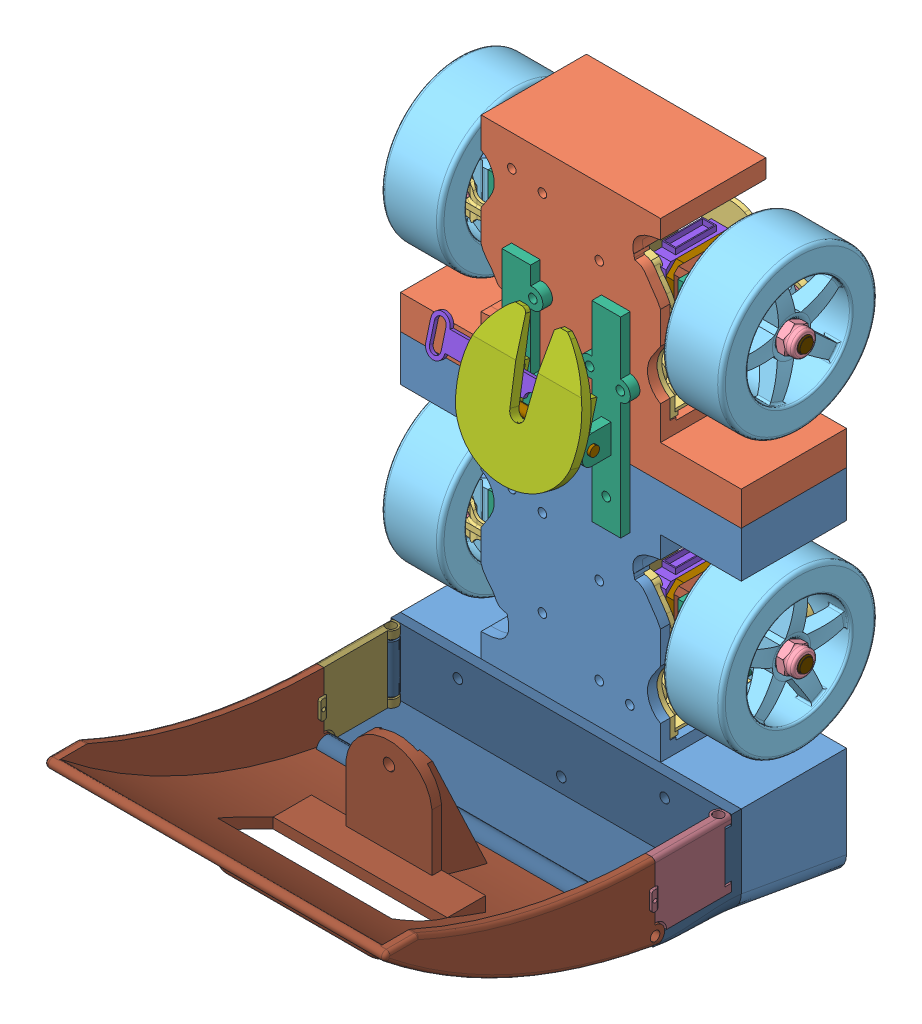
SolidWorks assembly Chassis assembly 2, configuration Default. Lengths in mm.
Overall size (185.37 311.7 273.69).
160 component instances, 31 part files, 34 mates.
Components (placement in the parent):
- Dolly chassis half 1-1: Dolly chassis half 1 [Default] at (2.6348 264.5467 189.9496) size (178 185.23 55)
- Dolly chassis half 2-1: Dolly chassis half 2 [Default] at (2.6348 264.5467 189.9496) size (178 119.07 55)
- Module Assembly-1: Module Assembly [Default] at (-63.8652 93.3967 162.4496) x (0 -1 0) z (-1 0 0) size (68.25 51.28 97.81)
  - Housing-1: Housing [Default] at origin size (64.25 48.5 67.91)
  - Bearing 12x8-1: Bearing 12x8 [Default] at (0 -18.25 0.75) x (-0.914388 0 0.40484) z (-0.40484 0 -0.914388) size (12 3.5 12)
  - Spindle-1: Spindle [Default] at (0 2 0.75) size (49.04 45 20.5)
  - Spindle base-1: Spindle base [Default] at (0 2 -15.25) x (-1 0 0) z (0 -1 0) size (37.62 3.5 44.8)
  - Encoder-1: Encoder [Défaut] at (0 2 -12.48) x (0 1 0) z (0 0 1) size (28.68 37.25 10.4)
  - Wheel-1: Wheel [Default] at (0 2 -8.55) x (0.929787 0.368098 0) z (0.368098 -0.929787 0) size (81.5 31 81.5) (hidden)
  - Stepper Nema14-1: Stepper Nema14 [Predeterminado] at (4.764 -15.5 -30.1157) x (-1 0 0) z (0 1 0) size (37.8 40 35)
    - nema14_base-1: nema14_base [Predeterminado] at (-12.736 -8.6343 35) size (37.8 9 35)
    - nema14_centro-1: nema14_centro [Predeterminado] at (-12.736 0.3657 35) size (35 4 35)
    - nema14_eje-1: nema14_eje [Predeterminado] at (4.764 -6.6343 17.5) x (0 1 0) z (-0.939004 0 0.343907) size (38 5 5)
    - nema14_techo-1: nema14_techo [Predeterminado] at (-12.736 4.3657 35) size (35 9 35)
  - Servo motor-1: Servo motor [Default] at (-25.7048 26.288 -66.0832) x (0 0 1) z (1 0 0) size (11.5 29.2 32.5) (flexible)
    - TowerPro-SG90-Body-1: TowerPro-SG90-Body [Default] at (13.6721 7.288 30.7048) size (11.5 26 32.5)
    - ServoFinalGear-1: ServoFinalGear [Default] at (13.6721 33.288 25.7048) x (0.607544 0 -0.794286) z (0.794286 0 0.607544) size (4.64 3.2 4.64)
  - Control arm-1: Control arm [Default] at (0 -7.5 -52.4111) x (0.891007 0 0.45399) z (0.45399 0 -0.891007) size (37.9 4.5 7.8)
  - Ball joint assy-1: Ball joint assy [Default] at (-26.7302 -5 -12.8697) x (-0.874356 0 0.485286) z (0.485286 0 0.874356) size (15.43 16.21 22.24) (flexible)
    - Ball-1: Ball [Default] at origin size (5.5 15.11 5.5)
    - Joint-1: Joint [Default] at (-3.8823 13.66 -6.9948) x (0.874356 0 -0.485286) z (0 -1 0) size (5.1 22.6 5.1)
  - Ball joint assy-2: Ball joint assy [Default] at (-26.7302 -5 -66.0308) x (-0.846813 0 0.531891) z (0.531891 0 0.846813) size (16.34 16.21 21.85) (flexible)
    - Ball-1: Ball [Default] at origin size (5.5 15.11 5.5)
    - Joint-1: Joint [Default] at (4.2551 13.66 6.7745) x (-0.846813 0 0.531891) z (0 -1 0) size (5.1 22.6 5.1)
  - Steering rod-1: Steering rod [Default] at (-26.7302 -18.66 -18.4608) x (-0.014502 0.999895 0) z (-0.999895 -0.014502 0) size (3 28.27 3)
  - Wheel adapter-1: Wheel adapter [Default] at (0 2 -13.8175) x (0.291296 -0.956633 0) z (-0.956633 -0.291296 0) size (8.34 40 8.37)
  - Wheel spacer-1: Wheel spacer [Default] at (0 2 12.25) x (0.368098 -0.929787 0) z (0.929787 0.368098 0) size (13.86 8 12)
  - M3x5 din 7984-1: M3x5 din 7984 [Default] at (15.31 20.9 -16.25) x (0.933505 0.358563 0) z (0 0 -1) size (5.5 5.5 7)
  - Housing lid-1: Housing lid [Default] at (0 4 0) x (-1 0 0) z (0 0 1) size (68.25 9.28 69.91)
  - Bearing 12x8-3: Bearing 12x8 [Default] at (0 22.25 0.75) x (-0.914388 0 0.40484) z (0.40484 0 0.914388) size (12 3.5 12)
  - M8 nut-1: M8 nut [Default] at (0 2 16.6825) x (-0.817347 -0.576146 0) z (0 0 1) size (13 16.06 8.5)
  - M3x5 din 7984-2: M3x5 din 7984 [Default] at (15.31 -16.9 -16.25) x (-0.933505 0.358563 0) z (0 0 -1) size (5.5 5.5 7)
  - M3x5 din 7984-3: M3x5 din 7984 [Default] at (-15.31 20.9 -16.25) x (0.933505 -0.358563 0) z (0 0 -1) size (5.5 5.5 7)
  - M3x5 din 7984-4: M3x5 din 7984 [Default] at (-15.31 -16.9 -16.25) x (-0.933505 -0.358563 0) z (0 0 -1) size (5.5 5.5 7)
  - M3x5 din 7984-5: M3x5 din 7984 [Default] at (-13 15 -17.75) x (0.999849 0.017374 0) z (0 0 1) size (5.5 5.5 7)
  - M3x5 din 7984-6: M3x5 din 7984 [Default] at (-13 -11 -17.75) x (-0.999849 0.017374 0) z (0 0 1) size (5.5 5.5 7)
  - M3x5 din 7984-7: M3x5 din 7984 [Default] at (13 15 -17.75) x (0.999849 -0.017374 0) z (0 0 1) size (5.5 5.5 7)
  - M3x5 din 7984-8: M3x5 din 7984 [Default] at (13 -11 -17.75) x (-0.999849 -0.017374 0) z (0 0 1) size (5.5 5.5 7)
- Module Assembly-2: Module Assembly [Default] at (69.1348 93.3967 162.4496) x (0 1 0) z (1 0 0) size (68.25 51.28 97.81)
  - Housing-1: Housing [Default] at origin size (64.25 48.5 67.91)
  - Bearing 12x8-1: Bearing 12x8 [Default] at (0 -18.25 0.75) x (-0.914388 0 0.40484) z (-0.40484 0 -0.914388) size (12 3.5 12)
  - Spindle-1: Spindle [Default] at (0 2 0.75) size (49.04 45 20.5)
  - Spindle base-1: Spindle base [Default] at (0 2 -15.25) x (-1 0 0) z (0 -1 0) size (37.62 3.5 44.8)
  - Encoder-1: Encoder [Défaut] at (0 2 -12.48) x (0 1 0) z (0 0 1) size (28.68 37.25 10.4)
  - Wheel-1: Wheel [Default] at (0 2 -8.55) x (0.929787 0.368098 0) z (0.368098 -0.929787 0) size (81.5 31 81.5) (hidden)
  - Stepper Nema14-1: Stepper Nema14 [Predeterminado] at (4.764 -15.5 -30.1157) x (-1 0 0) z (0 1 0) size (37.8 40 35)
    - nema14_base-1: nema14_base [Predeterminado] at (-12.736 -8.6343 35) size (37.8 9 35)
    - nema14_centro-1: nema14_centro [Predeterminado] at (-12.736 0.3657 35) size (35 4 35)
    - nema14_eje-1: nema14_eje [Predeterminado] at (4.764 -6.6343 17.5) x (0 1 0) z (-0.939004 0 0.343907) size (38 5 5)
    - nema14_techo-1: nema14_techo [Predeterminado] at (-12.736 4.3657 35) size (35 9 35)
  - Servo motor-1: Servo motor [Default] at (-25.7048 26.288 -66.0832) x (0 0 1) z (1 0 0) size (11.5 29.2 32.5) (flexible)
    - TowerPro-SG90-Body-1: TowerPro-SG90-Body [Default] at (13.6721 7.288 30.7048) size (11.5 26 32.5)
    - ServoFinalGear-1: ServoFinalGear [Default] at (13.6721 33.288 25.7048) x (0.607544 0 -0.794286) z (0.794286 0 0.607544) size (4.64 3.2 4.64)
  - Control arm-1: Control arm [Default] at (0 -7.5 -52.4111) x (0.891007 0 0.45399) z (0.45399 0 -0.891007) size (37.9 4.5 7.8)
  - Ball joint assy-1: Ball joint assy [Default] at (-26.7302 -5 -12.8697) x (-0.874356 0 0.485286) z (0.485286 0 0.874356) size (15.43 16.21 22.24) (flexible)
    - Ball-1: Ball [Default] at origin size (5.5 15.11 5.5)
    - Joint-1: Joint [Default] at (-3.8823 13.66 -6.9948) x (0.874356 0 -0.485286) z (0 -1 0) size (5.1 22.6 5.1)
  - Ball joint assy-2: Ball joint assy [Default] at (-26.7302 -5 -66.0308) x (-0.846813 0 0.531891) z (0.531891 0 0.846813) size (16.34 16.21 21.85) (flexible)
    - Ball-1: Ball [Default] at origin size (5.5 15.11 5.5)
    - Joint-1: Joint [Default] at (4.2551 13.66 6.7745) x (-0.846813 0 0.531891) z (0 -1 0) size (5.1 22.6 5.1)
  - Steering rod-1: Steering rod [Default] at (-26.7302 -18.66 -18.4608) x (-0.014502 0.999895 0) z (-0.999895 -0.014502 0) size (3 28.27 3)
  - Wheel adapter-1: Wheel adapter [Default] at (0 2 -13.8175) x (0.291296 -0.956633 0) z (-0.956633 -0.291296 0) size (8.34 40 8.37)
  - Wheel spacer-1: Wheel spacer [Default] at (0 2 12.25) x (0.368098 -0.929787 0) z (0.929787 0.368098 0) size (13.86 8 12)
  - M3x5 din 7984-1: M3x5 din 7984 [Default] at (15.31 20.9 -16.25) x (0.933505 0.358563 0) z (0 0 -1) size (5.5 5.5 7)
  - Housing lid-1: Housing lid [Default] at (0 4 0) x (-1 0 0) z (0 0 1) size (68.25 9.28 69.91)
  - Bearing 12x8-3: Bearing 12x8 [Default] at (0 22.25 0.75) x (-0.914388 0 0.40484) z (0.40484 0 0.914388) size (12 3.5 12)
  - M8 nut-1: M8 nut [Default] at (0 2 16.6825) x (-0.817347 -0.576146 0) z (0 0 1) size (13 16.06 8.5)
  - M3x5 din 7984-2: M3x5 din 7984 [Default] at (15.31 -16.9 -16.25) x (-0.933505 0.358563 0) z (0 0 -1) size (5.5 5.5 7)
  - M3x5 din 7984-3: M3x5 din 7984 [Default] at (-15.31 20.9 -16.25) x (0.933505 -0.358563 0) z (0 0 -1) size (5.5 5.5 7)
  - M3x5 din 7984-4: M3x5 din 7984 [Default] at (-15.31 -16.9 -16.25) x (-0.933505 -0.358563 0) z (0 0 -1) size (5.5 5.5 7)
  - M3x5 din 7984-5: M3x5 din 7984 [Default] at (-13 15 -17.75) x (0.999849 0.017374 0) z (0 0 1) size (5.5 5.5 7)
  - M3x5 din 7984-6: M3x5 din 7984 [Default] at (-13 -11 -17.75) x (-0.999849 0.017374 0) z (0 0 1) size (5.5 5.5 7)
  - M3x5 din 7984-7: M3x5 din 7984 [Default] at (13 15 -17.75) x (0.999849 -0.017374 0) z (0 0 1) size (5.5 5.5 7)
  - M3x5 din 7984-8: M3x5 din 7984 [Default] at (13 -11 -17.75) x (-0.999849 -0.017374 0) z (0 0 1) size (5.5 5.5 7)
- Module Assembly-3: Module Assembly [Default] at (69.1348 238.0467 162.4496) x (0 1 0) z (1 0 0) size (68.25 51.28 97.81)
  - Housing-1: Housing [Default] at origin size (64.25 48.5 67.91)
  - Bearing 12x8-1: Bearing 12x8 [Default] at (0 -18.25 0.75) x (-0.914388 0 0.40484) z (-0.40484 0 -0.914388) size (12 3.5 12)
  - Spindle-1: Spindle [Default] at (0 2 0.75) size (49.04 45 20.5)
  - Spindle base-1: Spindle base [Default] at (0 2 -15.25) x (-1 0 0) z (0 -1 0) size (37.62 3.5 44.8)
  - Encoder-1: Encoder [Défaut] at (0 2 -12.48) x (0 1 0) z (0 0 1) size (28.68 37.25 10.4)
  - Wheel-1: Wheel [Default] at (0 2 -8.55) x (0.929787 0.368098 0) z (0.368098 -0.929787 0) size (81.5 31 81.5) (hidden)
  - Stepper Nema14-1: Stepper Nema14 [Predeterminado] at (4.764 -15.5 -30.1157) x (-1 0 0) z (0 1 0) size (37.8 40 35)
    - nema14_base-1: nema14_base [Predeterminado] at (-12.736 -8.6343 35) size (37.8 9 35)
    - nema14_centro-1: nema14_centro [Predeterminado] at (-12.736 0.3657 35) size (35 4 35)
    - nema14_eje-1: nema14_eje [Predeterminado] at (4.764 -6.6343 17.5) x (0 1 0) z (-0.939004 0 0.343907) size (38 5 5)
    - nema14_techo-1: nema14_techo [Predeterminado] at (-12.736 4.3657 35) size (35 9 35)
  - Servo motor-1: Servo motor [Default] at (-25.7048 26.288 -66.0832) x (0 0 1) z (1 0 0) size (11.5 29.2 32.5) (flexible)
    - TowerPro-SG90-Body-1: TowerPro-SG90-Body [Default] at (13.6721 7.288 30.7048) size (11.5 26 32.5)
    - ServoFinalGear-1: ServoFinalGear [Default] at (13.6721 33.288 25.7048) x (0.607544 0 -0.794286) z (0.794286 0 0.607544) size (4.64 3.2 4.64)
  - Control arm-1: Control arm [Default] at (0 -7.5 -52.4111) x (0.891007 0 0.45399) z (0.45399 0 -0.891007) size (37.9 4.5 7.8)
  - Ball joint assy-1: Ball joint assy [Default] at (-26.7302 -5 -12.8697) x (-0.874356 0 0.485286) z (0.485286 0 0.874356) size (15.43 16.21 22.24) (flexible)
    - Ball-1: Ball [Default] at origin size (5.5 15.11 5.5)
    - Joint-1: Joint [Default] at (-3.8823 13.66 -6.9948) x (0.874356 0 -0.485286) z (0 -1 0) size (5.1 22.6 5.1)
  - Ball joint assy-2: Ball joint assy [Default] at (-26.7302 -5 -66.0308) x (-0.846813 0 0.531891) z (0.531891 0 0.846813) size (16.34 16.21 21.85) (flexible)
    - Ball-1: Ball [Default] at origin size (5.5 15.11 5.5)
    - Joint-1: Joint [Default] at (4.2551 13.66 6.7745) x (-0.846813 0 0.531891) z (0 -1 0) size (5.1 22.6 5.1)
  - Steering rod-1: Steering rod [Default] at (-26.7302 -18.66 -18.4608) x (-0.014502 0.999895 0) z (-0.999895 -0.014502 0) size (3 28.27 3)
  - Wheel adapter-1: Wheel adapter [Default] at (0 2 -13.8175) x (0.291296 -0.956633 0) z (-0.956633 -0.291296 0) size (8.34 40 8.37)
  - Wheel spacer-1: Wheel spacer [Default] at (0 2 12.25) x (0.368098 -0.929787 0) z (0.929787 0.368098 0) size (13.86 8 12)
  - M3x5 din 7984-1: M3x5 din 7984 [Default] at (15.31 20.9 -16.25) x (0.933505 0.358563 0) z (0 0 -1) size (5.5 5.5 7)
  - Housing lid-1: Housing lid [Default] at (0 4 0) x (-1 0 0) z (0 0 1) size (68.25 9.28 69.91)
  - Bearing 12x8-3: Bearing 12x8 [Default] at (0 22.25 0.75) x (-0.914388 0 0.40484) z (0.40484 0 0.914388) size (12 3.5 12)
  - M8 nut-1: M8 nut [Default] at (0 2 16.6825) x (-0.817347 -0.576146 0) z (0 0 1) size (13 16.06 8.5)
  - M3x5 din 7984-2: M3x5 din 7984 [Default] at (15.31 -16.9 -16.25) x (-0.933505 0.358563 0) z (0 0 -1) size (5.5 5.5 7)
  - M3x5 din 7984-3: M3x5 din 7984 [Default] at (-15.31 20.9 -16.25) x (0.933505 -0.358563 0) z (0 0 -1) size (5.5 5.5 7)
  - M3x5 din 7984-4: M3x5 din 7984 [Default] at (-15.31 -16.9 -16.25) x (-0.933505 -0.358563 0) z (0 0 -1) size (5.5 5.5 7)
  - M3x5 din 7984-5: M3x5 din 7984 [Default] at (-13 15 -17.75) x (0.999849 0.017374 0) z (0 0 1) size (5.5 5.5 7)
  - M3x5 din 7984-6: M3x5 din 7984 [Default] at (-13 -11 -17.75) x (-0.999849 0.017374 0) z (0 0 1) size (5.5 5.5 7)
  - M3x5 din 7984-7: M3x5 din 7984 [Default] at (13 15 -17.75) x (0.999849 -0.017374 0) z (0 0 1) size (5.5 5.5 7)
  - M3x5 din 7984-8: M3x5 din 7984 [Default] at (13 -11 -17.75) x (-0.999849 -0.017374 0) z (0 0 1) size (5.5 5.5 7)
- Module Assembly-4: Module Assembly [Default] at (-63.8652 238.0467 162.4496) x (0 -1 0) z (-1 0 0) size (68.25 51.28 97.81)
  - Housing-1: Housing [Default] at origin size (64.25 48.5 67.91)
  - Bearing 12x8-1: Bearing 12x8 [Default] at (0 -18.25 0.75) x (-0.914388 0 0.40484) z (-0.40484 0 -0.914388) size (12 3.5 12)
  - Spindle-1: Spindle [Default] at (0 2 0.75) size (49.04 45 20.5)
  - Spindle base-1: Spindle base [Default] at (0 2 -15.25) x (-1 0 0) z (0 -1 0) size (37.62 3.5 44.8)
  - Encoder-1: Encoder [Défaut] at (0 2 -12.48) x (0 1 0) z (0 0 1) size (28.68 37.25 10.4)
  - Wheel-1: Wheel [Default] at (0 2 -8.55) x (0.929787 0.368098 0) z (0.368098 -0.929787 0) size (81.5 31 81.5) (hidden)
  - Stepper Nema14-1: Stepper Nema14 [Predeterminado] at (4.764 -15.5 -30.1157) x (-1 0 0) z (0 1 0) size (37.8 40 35)
    - nema14_base-1: nema14_base [Predeterminado] at (-12.736 -8.6343 35) size (37.8 9 35)
    - nema14_centro-1: nema14_centro [Predeterminado] at (-12.736 0.3657 35) size (35 4 35)
    - nema14_eje-1: nema14_eje [Predeterminado] at (4.764 -6.6343 17.5) x (0 1 0) z (-0.939004 0 0.343907) size (38 5 5)
    - nema14_techo-1: nema14_techo [Predeterminado] at (-12.736 4.3657 35) size (35 9 35)
  - Servo motor-1: Servo motor [Default] at (-25.7048 26.288 -66.0832) x (0 0 1) z (1 0 0) size (11.5 29.2 32.5) (flexible)
    - TowerPro-SG90-Body-1: TowerPro-SG90-Body [Default] at (13.6721 7.288 30.7048) size (11.5 26 32.5)
    - ServoFinalGear-1: ServoFinalGear [Default] at (13.6721 33.288 25.7048) x (0.607544 0 -0.794286) z (0.794286 0 0.607544) size (4.64 3.2 4.64)
  - Control arm-1: Control arm [Default] at (0 -7.5 -52.4111) x (0.891007 0 0.45399) z (0.45399 0 -0.891007) size (37.9 4.5 7.8)
  - Ball joint assy-1: Ball joint assy [Default] at (-26.7302 -5 -12.8697) x (-0.874356 0 0.485286) z (0.485286 0 0.874356) size (15.43 16.21 22.24) (flexible)
    - Ball-1: Ball [Default] at origin size (5.5 15.11 5.5)
    - Joint-1: Joint [Default] at (-3.8823 13.66 -6.9948) x (0.874356 0 -0.485286) z (0 -1 0) size (5.1 22.6 5.1)
  - Ball joint assy-2: Ball joint assy [Default] at (-26.7302 -5 -66.0308) x (-0.846813 0 0.531891) z (0.531891 0 0.846813) size (16.34 16.21 21.85) (flexible)
    - Ball-1: Ball [Default] at origin size (5.5 15.11 5.5)
    - Joint-1: Joint [Default] at (4.2551 13.66 6.7745) x (-0.846813 0 0.531891) z (0 -1 0) size (5.1 22.6 5.1)
  - Steering rod-1: Steering rod [Default] at (-26.7302 -18.66 -18.4608) x (-0.014502 0.999895 0) z (-0.999895 -0.014502 0) size (3 28.27 3)
  - Wheel adapter-1: Wheel adapter [Default] at (0 2 -13.8175) x (0.291296 -0.956633 0) z (-0.956633 -0.291296 0) size (8.34 40 8.37)
  - Wheel spacer-1: Wheel spacer [Default] at (0 2 12.25) x (0.368098 -0.929787 0) z (0.929787 0.368098 0) size (13.86 8 12)
  - M3x5 din 7984-1: M3x5 din 7984 [Default] at (15.31 20.9 -16.25) x (0.933505 0.358563 0) z (0 0 -1) size (5.5 5.5 7)
  - Housing lid-1: Housing lid [Default] at (0 4 0) x (-1 0 0) z (0 0 1) size (68.25 9.28 69.91)
  - Bearing 12x8-3: Bearing 12x8 [Default] at (0 22.25 0.75) x (-0.914388 0 0.40484) z (0.40484 0 0.914388) size (12 3.5 12)
  - M8 nut-1: M8 nut [Default] at (0 2 16.6825) x (-0.817347 -0.576146 0) z (0 0 1) size (13 16.06 8.5)
  - M3x5 din 7984-2: M3x5 din 7984 [Default] at (15.31 -16.9 -16.25) x (-0.933505 0.358563 0) z (0 0 -1) size (5.5 5.5 7)
  - M3x5 din 7984-3: M3x5 din 7984 [Default] at (-15.31 20.9 -16.25) x (0.933505 -0.358563 0) z (0 0 -1) size (5.5 5.5 7)
  - M3x5 din 7984-4: M3x5 din 7984 [Default] at (-15.31 -16.9 -16.25) x (-0.933505 -0.358563 0) z (0 0 -1) size (5.5 5.5 7)
  - M3x5 din 7984-5: M3x5 din 7984 [Default] at (-13 15 -17.75) x (0.999849 0.017374 0) z (0 0 1) size (5.5 5.5 7)
  - M3x5 din 7984-6: M3x5 din 7984 [Default] at (-13 -11 -17.75) x (-0.999849 0.017374 0) z (0 0 1) size (5.5 5.5 7)
  - M3x5 din 7984-7: M3x5 din 7984 [Default] at (13 15 -17.75) x (0.999849 -0.017374 0) z (0 0 1) size (5.5 5.5 7)
  - M3x5 din 7984-8: M3x5 din 7984 [Default] at (13 -11 -17.75) x (-0.999849 -0.017374 0) z (0 0 1) size (5.5 5.5 7)
- Wheel-1: Wheel [Default] at (60.5848 93.3967 164.4496) x (0 0.146111 0.989268) z (0 0.989268 -0.146111) size (81.5 31 81.5)
- Wheel-2: Wheel [Default] at (60.5848 238.0467 164.4496) x (0 0.783676 -0.62117) z (0 -0.62117 -0.783676) size (81.5 31 81.5)
- Wheel-3: Wheel [Default] at (-55.3152 238.0467 164.4496) x (0 -0.929787 0.368098) z (0 -0.368098 -0.929787) size (81.5 31 81.5)
- Wheel-4: Wheel [Default] at (-55.3152 93.3967 164.4496) x (0 -0.783676 -0.62117) z (0 0.62117 -0.783676) size (81.5 31 81.5)
- Fifth_wheel_assembly-1: Fifth_wheel_assembly [Default] at (26.7306 135.1631 149.1448) x (-1 0 0) z (0 1 0) size (90.59 41.74 100)
  - Fifth_wheel_mount-1: Fifth_wheel_mount [Default] at (-6.9031 48.3048 102.7348) size (67.09 20 100)
  - Fifth_wheel_disk-1: Fifth_wheel_disk [Default] at (-5.9031 71.3457 44.4932) x (1 0 0) z (0 -0.255937 0.966694) size (66.74 23.06 75.99)
  - Fifth_wheel_kingpin-1: Fifth_wheel_kingpin [Default] at (-1.4031 62.5809 65.8769) x (1 0 0) z (0 -0.255937 0.966694) size (80 2 20)
  - Fifth_wheel_axle-1: Fifth_wheel_axle [Default] at (51.5969 60.8048 45.2348) x (0 0.948415 -0.31703) z (1 0 0) size (5 5 55)
- front assembly 2-1: front assembly 2 [Default] at (-66.6874 152.8407 117.1017) x (1 0 0) z (0 -1 0) size (181 187.95 83.28) (flexible)
  - Foldable front base 2-1: Foldable front base 2 [Default] at (158.3211 77.8479 159.546) size (179.15 52.01 49.18)
  - foldable front flap 2-1: foldable front flap 2 [Default] at (69.3211 122.8479 151.0232) x (-1 0 0) z (0 0 -1) size (178.61 145.94 74.18)
  - Foldable front side flap right 2-1: Foldable front side flap right 2 [Default] at (-17.1789 86.3479 110.946) x (0 0 1) z (-1 0 0) size (35 43 8.5)
  - Foldable front side flap left 2-1: Foldable front side flap left 2 [Default] at (155.8211 86.3479 145.946) x (0 0 -1) z (1 0 0) size (35 43 8.5)
Mates (geometry in assembly coordinates):
- Coincident1: coincident: plane of Dolly chassis half 1-1 through (-44.2041 168.828 -11.5535) normal (0 1 0); plane of Dolly chassis half 2-1 through (-44.2041 168.828 -67.8767) normal (0 -1 0)
- Coincident2: coincident: plane of Dolly chassis half 1-1 through (2.6348 264.5467 194.9496) normal (0 0 1); plane of Dolly chassis half 2-1 through (2.6348 264.5467 194.9496) normal (0 0 1)
- Coincident3: coincident: plane of Dolly chassis half 1-1 through (49.4737 264.5467 194.9496) normal (1 0 0); plane of Dolly chassis half 2-1 through (49.4737 264.5467 194.9496) normal (1 0 0)
- Coincident4: coincident: plane of Dolly chassis half 1-1 through (2.6348 264.5467 189.9496) normal (0 0 -1); plane of Module Assembly-1/Housing lid-1 through (-63.8652 93.3967 189.9496) normal (0 0 1)
- Coincident5: coincident: plane of Dolly chassis half 1-1 through (-44.2041 264.5467 194.9496) normal (-1 0 0); plane of Module Assembly-1/Housing lid-1 through (-44.2041 93.3967 187.4496) normal (-1 0 0)
- Coincident6: coincident: plane of Dolly chassis half 1-1 through (49.4737 119.8967 194.9496) normal (1 0 0); plane of Module Assembly-2/Housing lid-1 through (49.4737 93.3967 187.4496) normal (1 0 0)
- Coincident7: coincident: plane of Dolly chassis half 1-1 through (2.6348 264.5467 189.9496) normal (0 0 -1); plane of Module Assembly-2/Housing lid-1 through (69.1348 93.3967 189.9496) normal (0 0 1)
- Coincident8: coincident: plane of Dolly chassis half 2-1 through (2.6348 264.5467 189.9496) normal (0 0 -1); plane of Module Assembly-3/Housing lid-1 through (69.1348 238.0467 189.9496) normal (0 0 1)
- Coincident9: coincident: plane of Dolly chassis half 2-1 through (49.4737 264.5467 194.9496) normal (1 0 0); plane of Module Assembly-3/Housing lid-1 through (49.4737 238.0467 187.4496) normal (1 0 0)
- Coincident10: coincident: plane of Dolly chassis half 2-1 through (-44.2041 264.5467 194.9496) normal (-1 0 0); plane of Module Assembly-4/Housing lid-1 through (-44.2041 238.0467 187.4496) normal (-1 0 0)
- Coincident11: coincident: plane of Dolly chassis half 1-1 through (2.6348 264.5467 189.9496) normal (0 0 -1); plane of Module Assembly-4/Housing lid-1 through (-63.8652 238.0467 189.9496) normal (0 0 1)
- Concentric5: concentric: cylinder of Module Assembly-2/Wheel adapter-1 through (55.3173 93.3967 164.4496) axis (-1 0 0) radius 4; cylinder of Wheel-1 through (60.5848 93.3967 164.4496) axis (1 0 0) radius 4
- Coincident15: coincident: plane of Module Assembly-2/Wheel spacer-1 through (73.3848 90.8464 170.8913) normal (0 0.146111 0.989268); plane of Wheel-1 through (81.3848 90.8464 170.8913) normal (0 -0.146111 -0.989268)
- Coincident16: coincident: plane of Module Assembly-2/Wheel spacer-1 through (81.3848 93.3967 164.4496) normal (1 0 0); plane of Wheel-1 through (81.3848 93.3967 164.4496) normal (-1 0 0)
- Concentric6: concentric: cylinder of Module Assembly-3/Wheel adapter-1 through (55.3173 238.0467 164.4496) axis (-1 0 0) radius 4; cylinder of Wheel-2 through (60.5848 238.0467 164.4496) axis (1 0 0) radius 4
- Coincident17: coincident: plane of Module Assembly-3/Wheel spacer-1 through (73.3848 235.4964 170.8913) normal (0 0.146111 0.989268); plane of Wheel-2 through (81.3848 235.4964 170.8913) normal (0 -0.146111 -0.989268)
- Coincident18: coincident: plane of Module Assembly-3/Wheel spacer-1 through (81.3848 238.0467 164.4496) normal (1 0 0); plane of Wheel-2 through (81.3848 238.0467 164.4496) normal (-1 0 0)
- Concentric7: concentric: cylinder of Module Assembly-4/Wheel adapter-1 through (-50.0477 238.0467 164.4496) axis (1 0 0) radius 4; cylinder of Wheel-3 through (-55.3152 238.0467 164.4496) axis (-1 0 0) radius 4
- Coincident19: coincident: plane of Module Assembly-4/Wheel spacer-1 through (-68.1152 240.5969 170.8913) normal (0 -0.146111 0.989268); plane of Wheel-3 through (-76.1152 240.5969 170.8913) normal (0 0.146111 -0.989268)
- Coincident20: coincident: plane of Module Assembly-4/Wheel spacer-1 through (-76.1152 238.0467 164.4496) normal (-1 0 0); plane of Wheel-3 through (-76.1152 238.0467 164.4496) normal (1 0 0)
- Concentric8: concentric: cylinder of Module Assembly-1/Wheel adapter-1 through (-50.0477 93.3967 164.4496) axis (1 0 0) radius 4; cylinder of Wheel-4 through (-55.3152 93.3967 164.4496) axis (-1 0 0) radius 4
- Coincident21: coincident: plane of Module Assembly-1/Wheel spacer-1 through (-68.1152 95.9469 170.8913) normal (0 -0.146111 0.989268); plane of Wheel-4 through (-76.1152 95.9469 170.8913) normal (0 0.146111 -0.989268)
- Coincident22: coincident: plane of Module Assembly-1/Wheel spacer-1 through (-76.1152 93.3967 164.4496) normal (-1 0 0); plane of Wheel-4 through (-76.1152 93.3967 164.4496) normal (1 0 0)
- Coincident23: coincident: plane of Dolly chassis half 2-1 through (2.6348 264.5467 194.9496) normal (0 0 1); plane of Fifth_wheel_assembly-1/Fifth_wheel_mount-1 through (33.6337 237.898 194.9496) normal (0 0 -1)
- Parallel2: parallel: plane of Dolly chassis half 2-1 through (2.6348 287.898 189.9496) normal (0 1 0); plane of Fifth_wheel_assembly-1/Fifth_wheel_mount-1 through (33.6337 237.898 199.9496) normal (0 1 0)
- Distance1: distance = 50 mm: plane of Fifth_wheel_assembly-1/Fifth_wheel_mount-1 through (33.6337 237.898 199.9496) normal (0 1 0); plane of Dolly chassis half 2-1 through (2.6348 287.898 189.9496) normal (0 1 0)
- Coincident24: coincident: plane of Dolly chassis half 1-1 through (2.6348 264.5467 194.9496) normal (0 0 1); plane of front assembly 2-1/Foldable front base 2-1 through (91.6337 -6.7054 194.9496) normal (0 0 -1)
- Coincident25: coincident: plane of Dolly chassis half 1-1 through (91.6337 264.5467 189.9496) normal (1 0 0); plane of front assembly 2-1/Foldable front base 2-1 through (91.6337 -6.7054 239.9496) normal (1 0 0)
- Coincident26: coincident: plane of Dolly chassis half 1-1 through (147.4822 -6.7054 194.9496) normal (0 -0.984808 0.173648); plane of front assembly 2-1/Foldable front base 2-1 through (91.6337 -6.7054 194.9496) normal (0 -0.984808 0.173648)
- Distance2: distance = 58 mm: plane of Fifth_wheel_assembly-1/Fifth_wheel_mount-1 through (33.6337 237.898 199.9496) normal (1 0 0); plane of Dolly chassis half 1-1 through (91.6337 264.5467 189.9496) normal (1 0 0)
- Concentric9: concentric: cylinder of Dolly chassis half 2-1 through (17.4737 252.7967 194.9496) axis (0 0 -1) radius 2.25; cylinder of Module Assembly-3/Housing lid-1 through (17.4737 252.7967 181.6496) axis (0 0 1) radius 2.8
- Concentric10: concentric: cylinder of Dolly chassis half 2-1 through (-28.2041 271.5467 194.9496) axis (0 0 -1) radius 2.25; cylinder of Module Assembly-4/Housing lid-1 through (-28.2041 271.5467 180.9496) axis (0 0 1) radius 2.8
- Concentric11: concentric: cylinder of Dolly chassis half 1-1 through (17.4737 62.8967 194.9496) axis (0 0 -1) radius 2.25; cylinder of Module Assembly-2/Housing lid-1 through (17.4737 62.8967 180.9496) axis (0 0 1) radius 2.8
- Concentric12: concentric: cylinder of Dolly chassis half 1-1 through (-12.2041 78.6467 194.9496) axis (0 0 -1) radius 2.25; cylinder of Module Assembly-1/Housing lid-1 through (-12.2041 78.6467 181.6496) axis (0 0 1) radius 2.8
